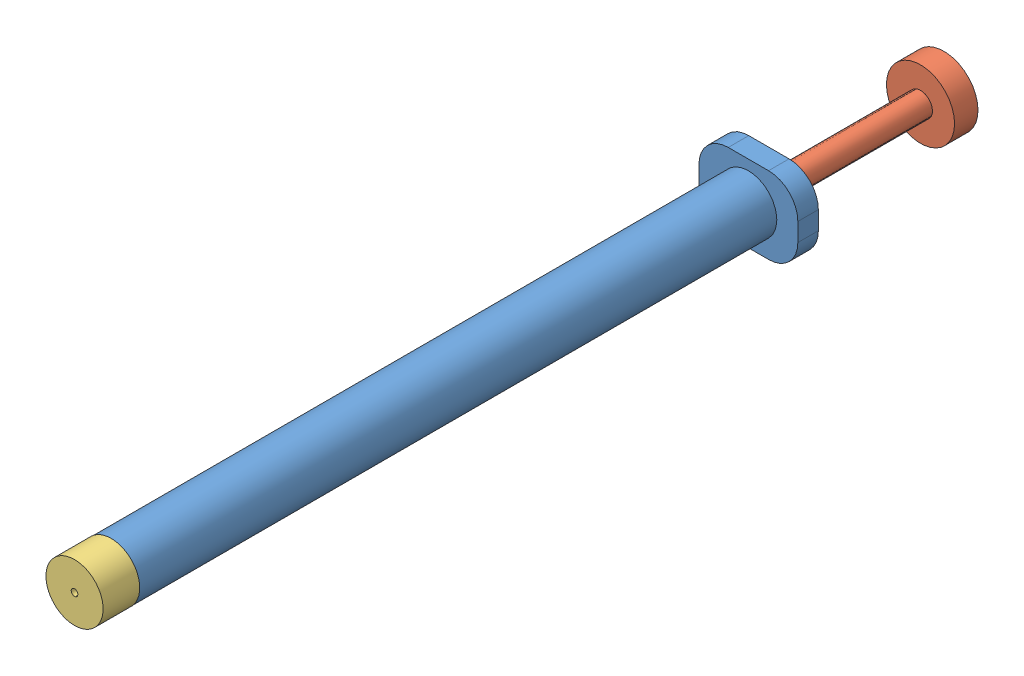
SolidWorks assembly Syringe, configuration Default. Lengths in mm.
Overall size (13.5 10.78 118.7).
3 component instances, 3 part files, 6 mates.
Components (placement in the parent):
- SyringeBase-1: SyringeBase [Default] at (-6.75 -5.25 -44.9) size (13.5 10.5 89.8)
- Plunger-1: Plunger [Default] at (0 0 -68.7957) x (0.98462 -0.17471 0) z (0 0 1) size (9.3 9.3 99.2)
- RNNut-1: RNNut [Default] at (0 0 44.9) x (0.394612 0.918848 0) z (0 0 1) size (7.8 7.8 5)
Mates (geometry in assembly coordinates):
- Coincident6: coincident anti-aligned: plane of Syringe Base-1 through (-6.75 -5.25 0) normal (0 0 -1)
- Coincident7: coincident aligned: plane of Syringe Base-1 through (-6.75 0 -44.9) normal (0 1 0)
- Coincident8: coincident aligned: plane of Syringe Base-1 through (0 -5.25 -44.9) normal (1 0 0)
- Concentric1: concentric anti-aligned: cylinder of Syringe Base-1 through (0 0 -44.9) axis (0 0 1) radius 1.63; cylinder of Plunger-1 through (0 0 30.4043) axis (0 0 -1) radius 1.63
- Coincident9: coincident anti-aligned: plane of Syringe Base-1 through (0 0 44.9) normal (0 0 1); plane of RN Nut-1 through (0 0 44.9) normal (0 0 -1)
- Concentric2: concentric aligned: cylinder of Syringe Base-1 through (0 0 44.9) axis (0 0 -1) radius 3.875; cylinder of RN Nut-1 through (0 0 49.9) axis (0 0 -1) radius 3.9
